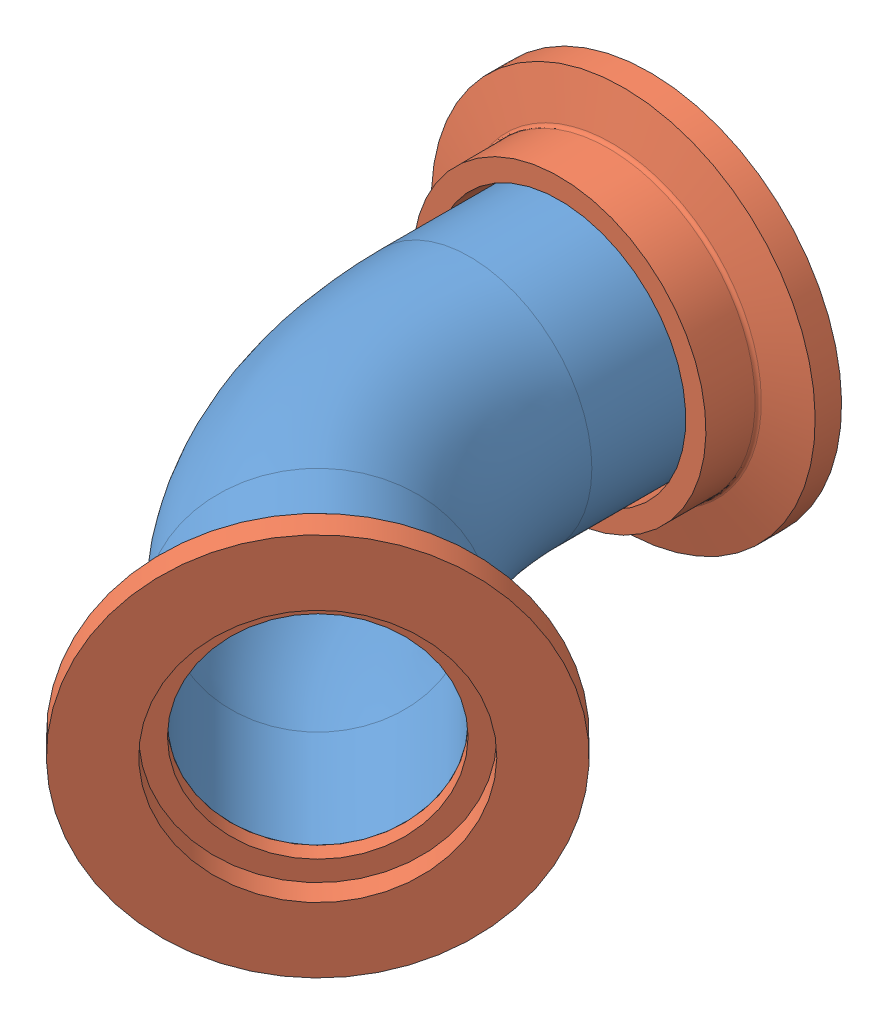
SolidWorks assembly 723015, configuration Default. Lengths in mm.
Overall size (63.45 45.79 75.05).
3 component instances, 2 part files, 4 mates.
Components (placement in the parent):
- 042202-1: 042202 [Default] at (12.3264 29.9922 18.0204) size (43.02 25.4 60.49)
- 972301-1: 972301 [Default] at (12.3264 29.9922 13.7024) x (0 0 1) z (-0.9869 0.161333 0) size (9.4 39.88 39.88)
- 972301-2: 972301 [Default] at (36.7168 29.9922 72.5859) x (-0.707107 0 -0.707107) z (0.698079 -0.159286 -0.698079) size (9.4 39.88 39.88)
Mates (geometry in assembly coordinates):
- Concentric1: concentric: circle of 042202-1; circle of 972301-2
- Coincident1: coincident anti-aligned: plane of 042202-1 through (33.6635 29.9922 69.5326) normal (0.707107 0 0.707107); plane of 972301-2 through (34.9079 40.9001 68.2882) normal (-0.707107 0 -0.707107)
- Concentric2: concentric: cylinder of 042202-1; cylinder of 972301-1 through (12.3264 29.9922 13.7024) axis (0 0 -1) radius 15.24
- Coincident2: coincident anti-aligned: plane of 042202-1 through (12.3264 29.9922 18.0204) normal (0 0 -1); plane of 972301-1 through (14.1089 40.8964 18.0204) normal (0 0 1)
